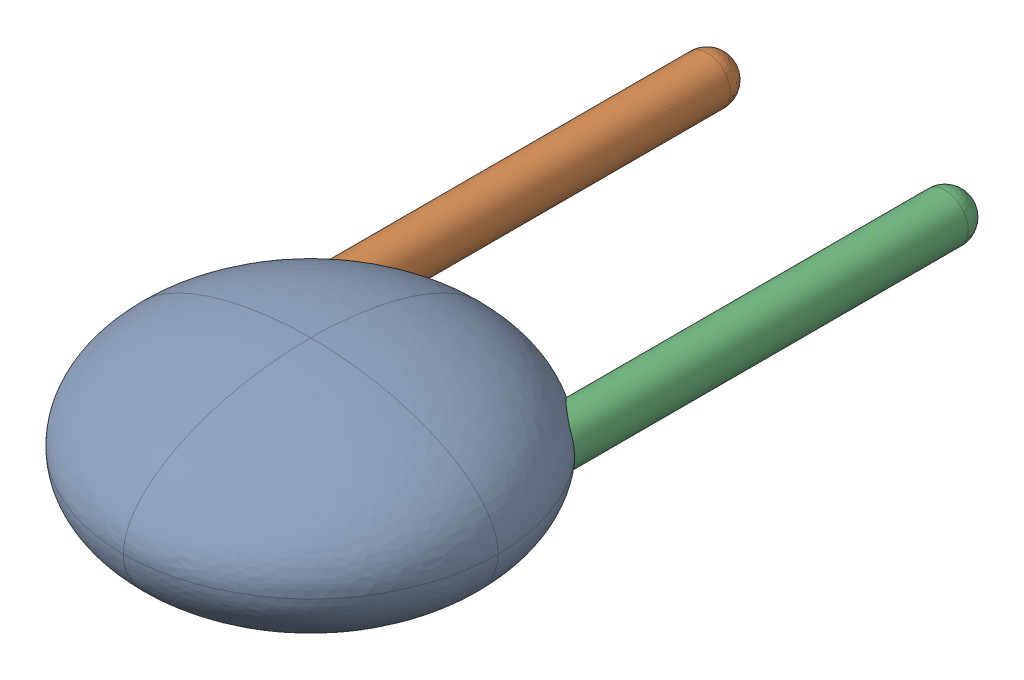
SolidWorks assembly C2, configuration Défaut. Lengths in mm.
Overall size (4 2 7.75).
4 component instances, 3 part files, 0 mates.
Components (placement in the parent):
- Open CASCADE STEP translator 6.8 1.3.1-1: Open CASCADE STEP translator 6.8 1.3.1 [Défaut] at origin size (4 2 7.75)
  - Body_1_2-1: Body_1_2 [Défaut] at (1.27 -1.27 0) x (0 1 0) z (0 0 1) size (2 4 4)
  - Pin_1-1: Pin_1 [Défaut] x (0 -1 0) z (0 0 1) size (0.5 0.5 5.5)
  - Pin_2-1: Pin_2 [Défaut] at (2.54 2.54 0) x (0 -1 0) z (0 0 1) size (0.5 0.5 5.5)
